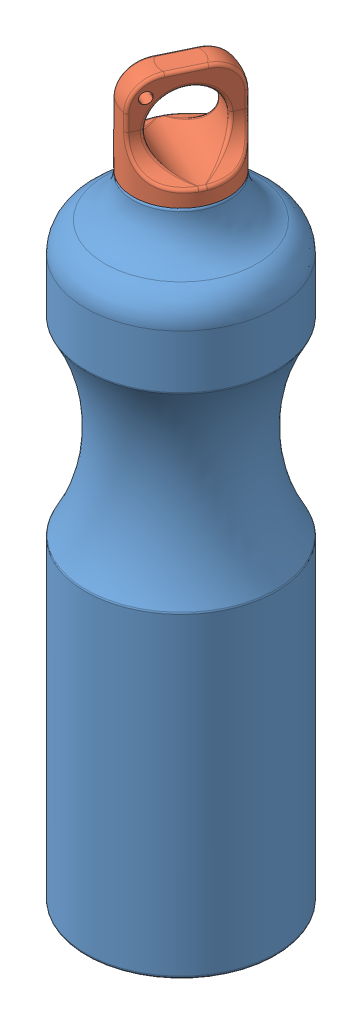
SolidWorks assembly full_bottle, configuration Default. Lengths in mm.
Overall size (60 230.67 60).
2 component instances, 2 part files, 2 mates.
Components (placement in the parent):
- body-1: body [Default] at origin size (60 200 60)
- cap-1: cap [Default] at (0 200 0) x (-0.434435 0 0.900703) z (-0.900703 0 -0.434435) size (30.47 30.67 30.51)
Mates (geometry in assembly coordinates):
- Concentric1: concentric aligned: cylinder of body-1 through (0 0 0) axis (0 -1 0) radius 30; cylinder of cap-1 through (0 230 0) axis (0 -1 0) radius 15
- Coincident2: coincident anti-aligned: plane of body-1 through (0 200 0) normal (0 1 0); plane of cap-1 through (0 200 0) normal (0 -1 0)
